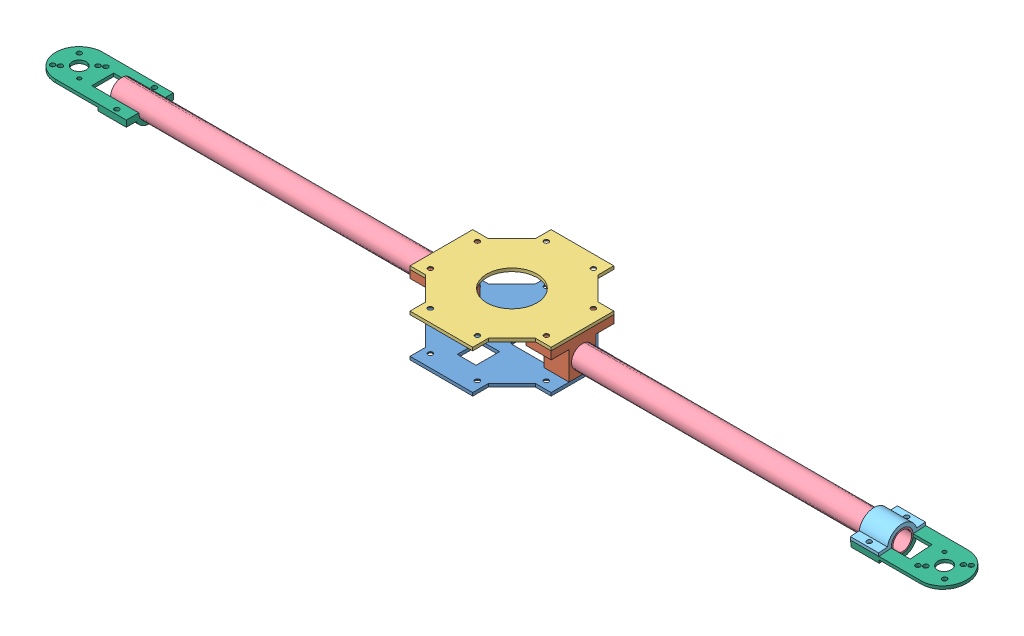
SolidWorks assembly helice_montagem, configuration Valor predeterminado. Lengths in mm.
Overall size (582 27 90).
9 component instances, 6 part files, 22 mates.
Components (placement in the parent):
- centro_helice_2-1: centro_helice_2 [Valor predeterminado] at (-6.0329 -3.7359 90) size (90 2 90)
- suporte_haste-1: suporte_haste [Valor predeterminado] at (22.9671 8.2641 90) x (0 0 -1) z (1 0 0) size (40 23 16)
- centro_helice_1-1: centro_helice_1 [Valor predeterminado] at (-6.0329 21.2641 90) size (90 2 90)
- suporte_haste-2: suporte_haste [Valor predeterminado] at (-51.0329 8.2641 90) x (0 0 -1) z (1 0 0) size (40 23 16)
- helice_haste-1: helice_haste [Valor predeterminado] at (242.9671 8.2641 90) x (0 -0.998136 -0.061023) z (-1 0 0) size (14 14 220)
- helice_haste-3: helice_haste [Valor predeterminado] at (-35.0329 8.2641 90) x (0 -0.416607 -0.909087) z (-1 0 0) size (14 14 220)
- suporte_helice_2-1: suporte_helice_2 [Valor predeterminado] at (224.9671 8.2087 90.7981) x (0 0.069251 -0.997599) z (1 0 0) size (30 9.5 18)
- suporte_helice-1: suporte_helice [Valor predeterminado] at (254.9671 8.2641 90) x (-1 0 0) z (0 -0.069251 0.997599) size (60 9.5 30)
- suporte_helice-2: suporte_helice [Valor predeterminado] at (-267.0329 8.2641 90) x (1 0 0) z (0 0 -1) size (60 9.5 30)
Mates (geometry in assembly coordinates):
- Concêntrico1: concentric aligned: circle of suporte_haste-1; circle of centro_helice_1-1
- Coincidente2: coincident anti-aligned: plane of suporte_haste-1 through (38.9671 21.2641 110) normal (0 1 0); plane of centro_helice_1-1 through (-6.0329 21.2641 90) normal (0 -1 0)
- Concêntrico3: concentric aligned: circle of suporte_haste-1; circle of centro_helice_1-1
- Coincidente5: coincident anti-aligned: plane of centro_helice_2-1 through (-6.0329 -1.7359 90) normal (0 1 0); plane of suporte_haste-1 through (38.9671 -1.7359 98.5) normal (0 -1 0)
- Coincidente7: coincident anti-aligned: line of centro_helice_2-1 through (38.9671 -1.7359 70) axis (0 0 1); line of suporte_haste-1 through (38.9671 -1.7359 89.5487) axis (0 0 -1)
- Concêntrico4: concentric aligned: circle of centro_helice_2-1; circle of suporte_haste-1
- Concêntrico5: concentric anti-aligned: circle of centro_helice_1-1; circle of suporte_haste-2
- Coincidente12: coincident anti-aligned: plane of centro_helice_1-1 through (-6.0329 21.2641 90) normal (0 -1 0); plane of suporte_haste-2 through (-35.0329 21.2641 110) normal (0 1 0)
- Paralelo2: parallel anti-aligned: line of centro_helice_2-1 through (-51.0329 -1.7359 70) axis (0 0 1); line of suporte_haste-2 through (-35.0329 -1.7359 98.5) axis (0 0 -1)
- Coincidente14: coincident aligned: plane of suporte_haste-1 through (22.9671 8.2641 90) normal (-1 0 0); plane of helice_haste-1 through (22.9671 8.2641 90) normal (-1 0 0)
- Concêntrico7: concentric anti-aligned: cylinder of suporte_haste-2 through (-35.0329 8.2641 90) axis (-1 0 0) radius 7; cylinder of helice_haste-3 through (-255.0329 8.2641 90) axis (1 0 0) radius 7
- Coincidente15: coincident aligned: plane of suporte_haste-2 through (-35.0329 8.2641 90) normal (1 0 0); plane of helice_haste-3 through (-35.0329 8.2641 90) normal (1 0 0)
- Concêntrico12: concentric aligned: cylinder of helice_haste-3 through (-255.0329 8.2641 90) axis (1 0 0) radius 7; cylinder of suporte_helice-2 through (-255.0329 8.2641 90) axis (1 0 0) radius 7
- Concêntrico15: concentric aligned: cylinder of helice_haste-3 through (-255.0329 8.2641 90) axis (1 0 0) radius 7; cylinder of suporte_helice-2 through (-255.0329 8.2641 90) axis (1 0 0) radius 7
- Concêntrico20: concentric anti-aligned: cylinder of helice_haste-1 through (22.9671 8.2641 90) axis (1 0 0) radius 7; cylinder of suporte_helice_2-1 through (242.9671 8.2641 90) axis (-1 0 0) radius 7
- Coincidente16: coincident aligned: plane of helice_haste-1 through (242.9671 8.2641 90) normal (1 0 0); plane of suporte_helice_2-1 through (242.9671 8.2641 90) normal (1 0 0)
- Concêntrico22: concentric anti-aligned: cylinder of helice_haste-1 through (22.9671 8.2641 90) axis (1 0 0) radius 7; cylinder of suporte_helice-1 through (242.9671 8.2641 90) axis (-1 0 0) radius 7
- Coincidente17: coincident aligned: plane of helice_haste-1 through (242.9671 8.2641 90) normal (1 0 0); plane of suporte_helice-1 through (242.9671 8.2641 90) normal (1 0 0)
- Coincidente18: coincident anti-aligned: plane of suporte_helice_2-1 through (242.9671 7.2254 104.964) normal (0 -0.997599 -0.069251); plane of suporte_helice-1 through (269.9671 8.2641 90) normal (0 0.997599 0.069251)
- Concêntrico24: concentric aligned: cylinder of helice_haste-3 through (-255.0329 8.2641 90) axis (1 0 0) radius 7; cylinder of suporte_helice-2 through (-255.0329 8.2641 90) axis (1 0 0) radius 7
- Paralelo3: parallel anti-aligned: plane of centro_helice_2-1 through (-6.0329 -3.7359 90) normal (0 -1 0); plane of suporte_helice-2 through (-282.0329 8.2641 90) normal (0 1 0)
- Coincidente25: coincident aligned: plane of helice_haste-3 through (-255.0329 8.2641 90) normal (-1 0 0); plane of suporte_helice-2 through (-255.0329 8.2641 90) normal (-1 0 0)
